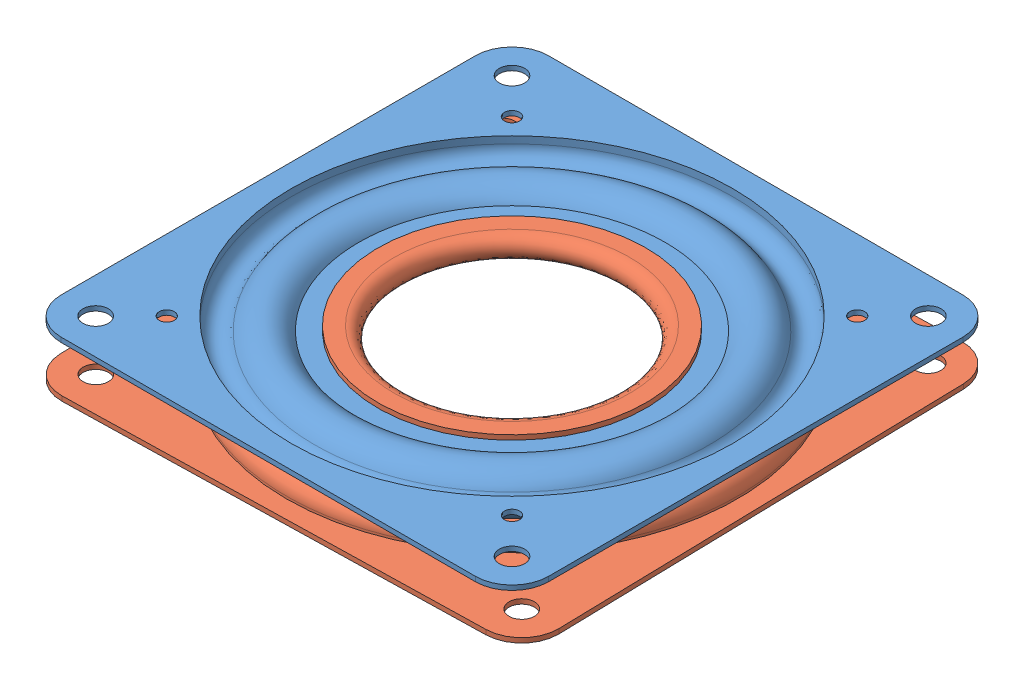
SolidWorks assembly turntable_bearing, configuration Default. Lengths in mm.
Overall size (145.66 7.87 145.66).
2 component instances, 2 part files, 2 mates.
Components (placement in the parent):
- turntable_bearing_half1-1: turntable_bearing_half1 [6031K31] at (-34.4079 16.559 6.8204) size (76.2 7.62 76.2)
- turntable_bearing_half2-1: turntable_bearing_half2 [6031K31] at (-34.4079 16.559 6.8204) x (0.723448 0 0.690379) z (-0.690379 0 0.723448) size (103.03 6.61 103.03)
Mates (geometry in assembly coordinates):
- Concentric1: concentric aligned: cylinder of turntable_bearing_half1-1 through (-34.4079 20.496 6.8204) axis (0 1 0) radius 34.5177; cylinder of turntable_bearing_half2-1 through (-34.4079 20.496 6.8204) axis (0 1 0) radius 34.5177
- Distance1: distance = 7.874 mm anti-aligned: plane of turntable_bearing_half2-1 through (-6.8446 12.622 33.1238) normal (0 -1 0); plane of turntable_bearing_half1-1 through (3.6921 20.496 6.8204) normal (0 1 0)
